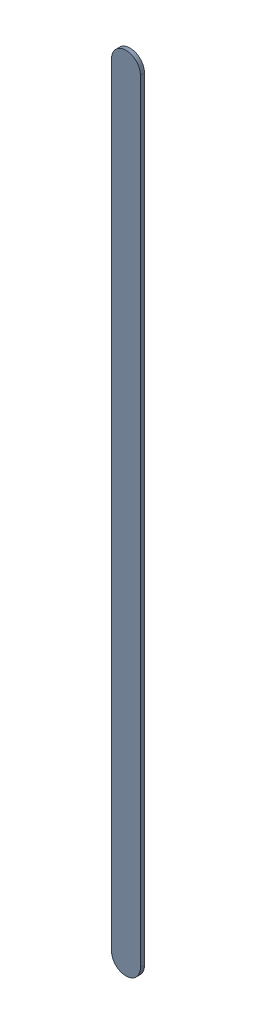
SolidWorks assembly Track (18.353mm,49.947mm)(18.353mm,56.749mm) on Top Layer, configuration Predeterminado. Lengths in mm.
Overall size (0.25 7.06 0.04).
2 component instances, 1 part files, 0 mates.
Components (placement in the parent):
- Track (18.353mm,49.947mm)(18.353mm,56.749mm) on Top Layer-1-1: Track (18.353mm,49.947mm)(18.353mm,56.749mm) on Top Layer-1 [Predeterminado] at (-68.317 -44.187 -0.0457) size (0.25 7.06 0.04)
  - Track (18.353mm,49.947mm)(18.353mm,56.749mm) on Top Layer-Part-1-1: Track (18.353mm,49.947mm)(18.353mm,56.749mm) on Top Layer-Part-1 [Predeterminado] at origin size (0.25 7.06 0.04)
